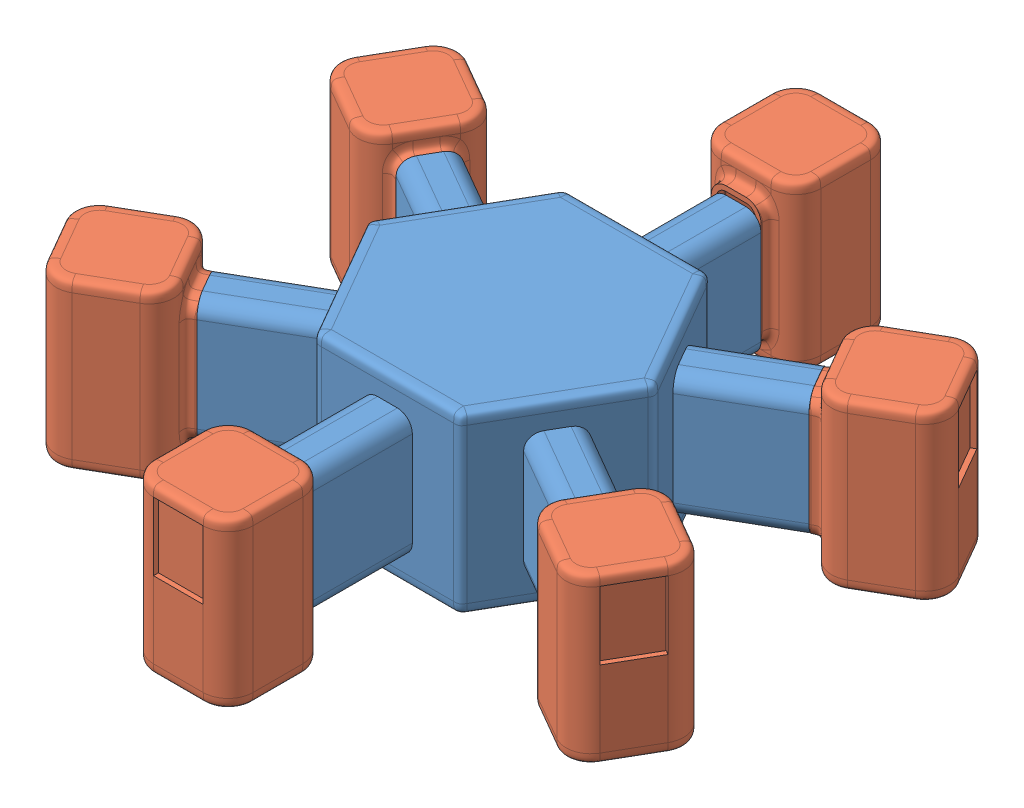
SolidWorks assembly New lander, configuration Default. Lengths in mm.
Overall size (12608.51 4571.44 13402.42).
10 component instances, 4 part files, 18 mates.
Components (placement in the parent):
- new main room-1: new main room [Default] at (4182.3692 4253.8732 6775.152) size (8294.99 3502 9000.21)
- New small room-1: New small room [Default] at (4181.1761 4353.8732 12475.1519) x (1 0 0.000209) z (-0.000209 0 1) size (2002 3313.64 2220.9)
- New small room-2: New small room [Default] at (-754.572 4353.8732 9624.1188) x (0.499819 0 0.86613) z (-0.86613 0 0.499819) size (2002 3313.64 2220.9)
- New small room-4: New small room [Default] at (-753.379 4276.934 3924.1189) x (-0.500181 0 0.865921) z (-0.865921 0 -0.500181) size (2002 3313.64 2220.9)
- New small room-5: New small room [Default] at (4183.5622 4518.4944 1075.1522) x (-1 0 -0.000209) z (0.000209 0 -1) size (2002 3313.64 2220.9)
- New small room-6: New small room [Default] at (9119.3104 4346.0861 3926.1853) x (-0.499819 0 -0.86613) z (0.86613 0 -0.499819) size (2002 3313.64 2220.9)
- New small room-7: New small room [Default] at (9118.1173 4369.164 9626.1852) x (0.500181 0 -0.865921) z (0.865921 0 0.500181) size (2002 3313.64 2220.9)
- Monitor-1: Monitor [Default] at (3268.5969 6494.9649 4415.4607) x (1 0 0.000209) z (-0.000209 0 1) size (832.46 503.65 50.76)
- Monitor-2: Monitor [Default] at (5125.6477 6515.7623 4415.8494) x (1 0 0.000209) z (-0.000209 0 1) size (832.46 503.65 50.76)
- SmallBox-3: SmallBox [Default] at (3568.422 3253.8732 7630.0862) size (1000 1000 1000)
Mates (geometry in assembly coordinates):
- Coincident1: coincident aligned: plane of new main room-1 through (4681.4273 5053.8732 11275.2566) normal (1 0 0.000209); plane of New small room-1 through (4681.4273 5053.8732 11275.2566) normal (1 0 0.000209)
- Coincident4: coincident anti-aligned: plane of new main room-1 through (3981.4273 5053.8732 11275.1101) normal (-0.000209 0 1); plane of New small room-1 through (4381.4273 5053.8732 11275.1938) normal (0.000209 0 -1)
- Tangent1: tangent: plane of new main room-1 through (3981.4273 7253.8732 11275.1101) normal (0 1 0); face of New small room-1
- Coincident5: coincident aligned: plane of new main room-1 through (34.8746 5053.8732 8591.2713) normal (-0.499819 0 -0.86613); plane of New small room-2 through (34.8746 5053.8732 8591.2713) normal (-0.499819 0 -0.86613)
- Coincident6: coincident anti-aligned: plane of new main room-1 through (184.8203 5053.8732 8851.1103) normal (-0.86613 0 0.499819); plane of New small room-2 through (384.7477 5053.8732 9197.5623) normal (0.86613 0 -0.499819)
- Tangent2: tangent: plane of new main room-1 through (184.8203 7253.8732 8851.1103) normal (0 1 0); face of New small room-2
- Coincident9: coincident anti-aligned: line of new main room-1 through (35.6353 5053.8732 4957.2968) axis (0 1 0); line of New small room-4 through (35.6353 6876.934 4957.2968) axis (0 -1 0)
- Coincident10: coincident anti-aligned: line of new main room-1 through (535.8165 6953.8732 4091.376) axis (0 -1 0); line of New small room-4 through (535.8165 4976.934 4091.376) axis (0 1 0)
- Coincident11: coincident anti-aligned: line of new main room-1 through (4683.3111 6953.8732 2275.2568) axis (0 -1 0); line of New small room-5 through (4683.3111 5218.4944 2275.2568) axis (0 1 0)
- Coincident12: coincident anti-aligned: line of new main room-1 through (3683.3111 5053.8732 2275.0475) axis (0 1 0); line of New small room-5 through (3683.3111 7118.4944 2275.0475) axis (0 -1 0)
- Coincident14: coincident anti-aligned: line of new main room-1 through (7830.045 5053.8732 4092.9028) axis (0 1 0); line of New small room-6 through (7830.045 6946.0861 4092.9028) axis (0 -1 0)
- Coincident15: coincident anti-aligned: line of new main room-1 through (8329.8637 6953.8732 4959.0328) axis (0 -1 0); line of New small room-6 through (8329.8637 5046.0861 4959.0328) axis (0 1 0)
- Coincident16: coincident anti-aligned: line of new main room-1 through (7828.9218 6953.8732 9458.9281) axis (0 -1 0); line of New small room-7 through (7828.9218 5069.164 9458.9281) axis (0 1 0)
- Coincident17: coincident anti-aligned: line of new main room-1 through (8329.1031 5053.8732 8593.0073) axis (0 1 0); line of New small room-7 through (8329.1031 6969.164 8593.0073) axis (0 -1 0)
- Coincident18: coincident anti-aligned: plane of new main room-1 through (5626.2472 7753.8732 4375.4542) normal (-0.000209 0 1); plane of Monitor-1 through (3468.6054 6266.9649 4375.0026) normal (0.000209 0 -1)
- Coincident20: coincident anti-aligned: plane of new main room-1 through (5626.2472 7753.8732 4375.4542) normal (-0.000209 0 1); plane of Monitor-2 through (5325.6562 6287.7623 4375.3913) normal (0.000209 0 -1)
- Parallel2: parallel aligned: line of Monitor-1 through (2863.5949 6247.9649 4424.876) axis (1 0 0.000209); line of Monitor-2 through (4720.6458 6268.7623 4425.2647) axis (1 0 0.000209)
- Coincident26: coincident anti-aligned: plane of new main room-1 through (4182.3692 4253.8732 6775.152) normal (0 -1 0); plane of SmallBox-3 through (3568.422 4253.8732 7630.0862) normal (0 1 0)
